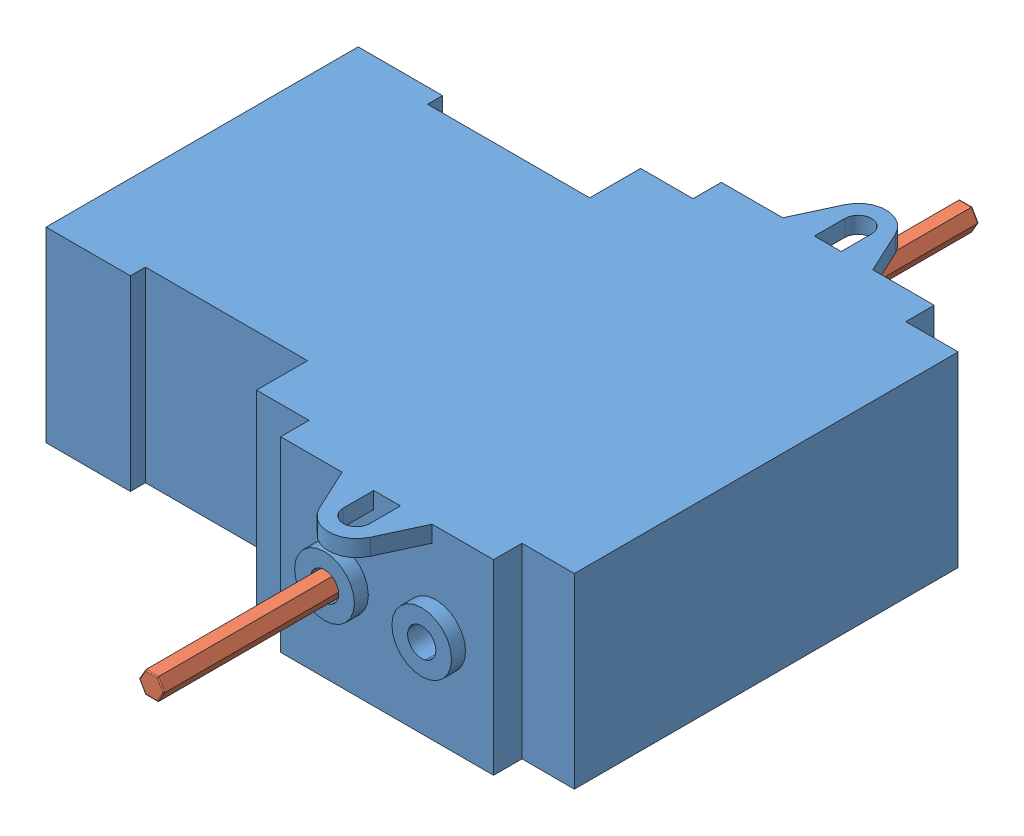
SolidWorks assembly Motor Assem, configuration Default. Lengths in mm.
Overall size (69.6 23.04 100.48).
2 component instances, 2 part files, 2 mates.
Components (placement in the parent):
- Motor Blank-1: Motor Blank [Default] at (5.7776 0.4066 -11.1507)
- Motor Shaft-1: Motor Shaft [Default] at (14.9851 11.9255 -61.3919) x (0 0 -1) z (1 0 0)
Mates (geometry in assembly coordinates):
- Concentric1: concentric: cylinder of Motor Blank-1 through (14.9851 11.9255 -40.0559) axis (0 0 1) radius 1.7526; circle of Motor Shaft-1
- Distance1: distance = 21.336 mm aligned: plane of Motor Shaft-1 through (13.4453 11.9255 39.0905) normal (0 0 1); plane of Motor Blank-1 through (14.9851 11.9255 17.7545) normal (0 0 1)
